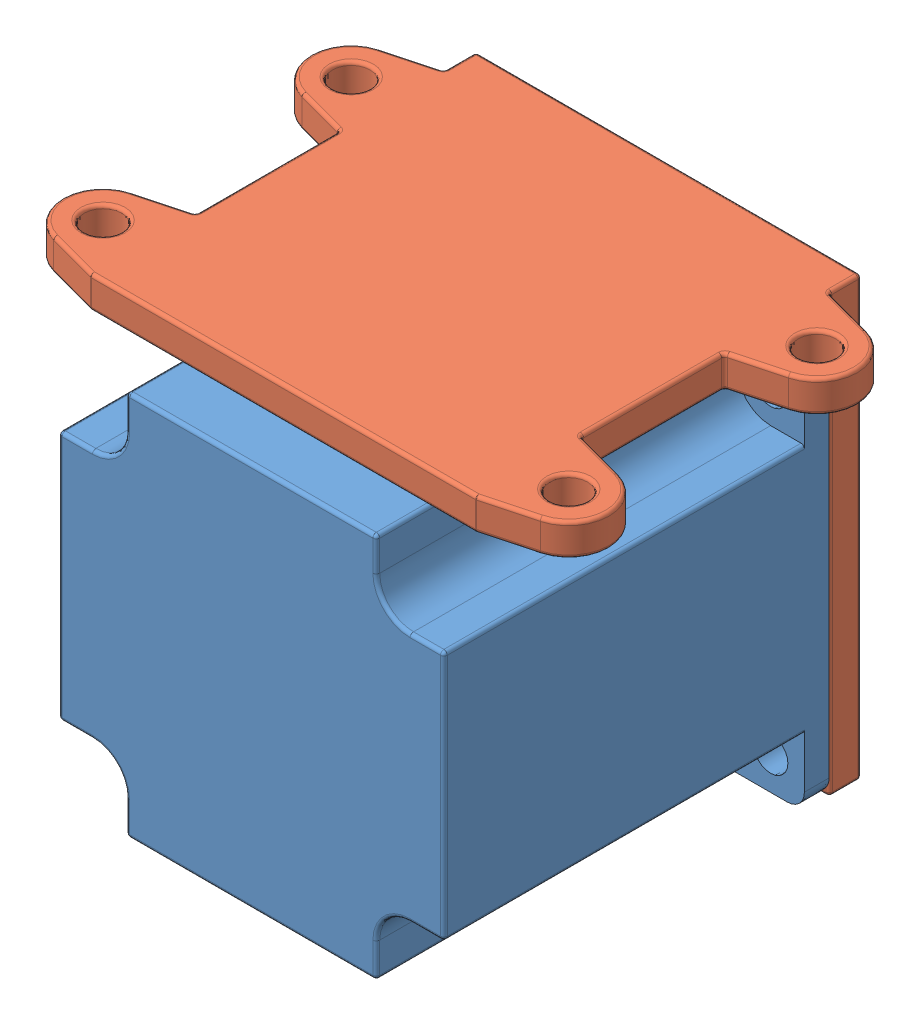
SolidWorks assembly motor_assembly, configuration Default. Lengths in mm.
Overall size (81.61 64.76 78).
2 component instances, 2 part files, 4 mates.
Components (placement in the parent):
- nema23-1: nema23 [Default] at (-21.698 -22.3647 8.644) size (57 57 78)
- motor_mount-1: motor_mount [Default] at (-21.698 13.8978 32.3815) x (1 0 0) z (0 -1 0) size (81.61 57 64.76)
Mates (geometry in assembly coordinates):
- Coincident4: coincident: plane of assembly; plane of assembly; plane of nema23-1 through (-21.698 -22.3647 8.644) normal (0 0 -1); plane of motor_mount-1 through (-50.198 -50.8647 8.644) normal (0 0 1)
- Coincident5: coincident: plane of assembly; plane of assembly; plane of nema23-1 through (-21.698 -22.3647 8.644) normal (0 0 -1); plane of motor_mount-1 through (-50.198 -50.8647 8.644) normal (0 0 1)
- Concentric3: concentric: circle of assembly; circle of assembly; circle of nema23-1; circle of motor_mount-1
- Parallel1: parallel: plane of assembly; plane of assembly; plane of nema23-1 through (-50.198 6.1353 65.644) normal (0 1 0); plane of motor_mount-1 through (-21.698 13.8978 32.3815) normal (0 1 0)
